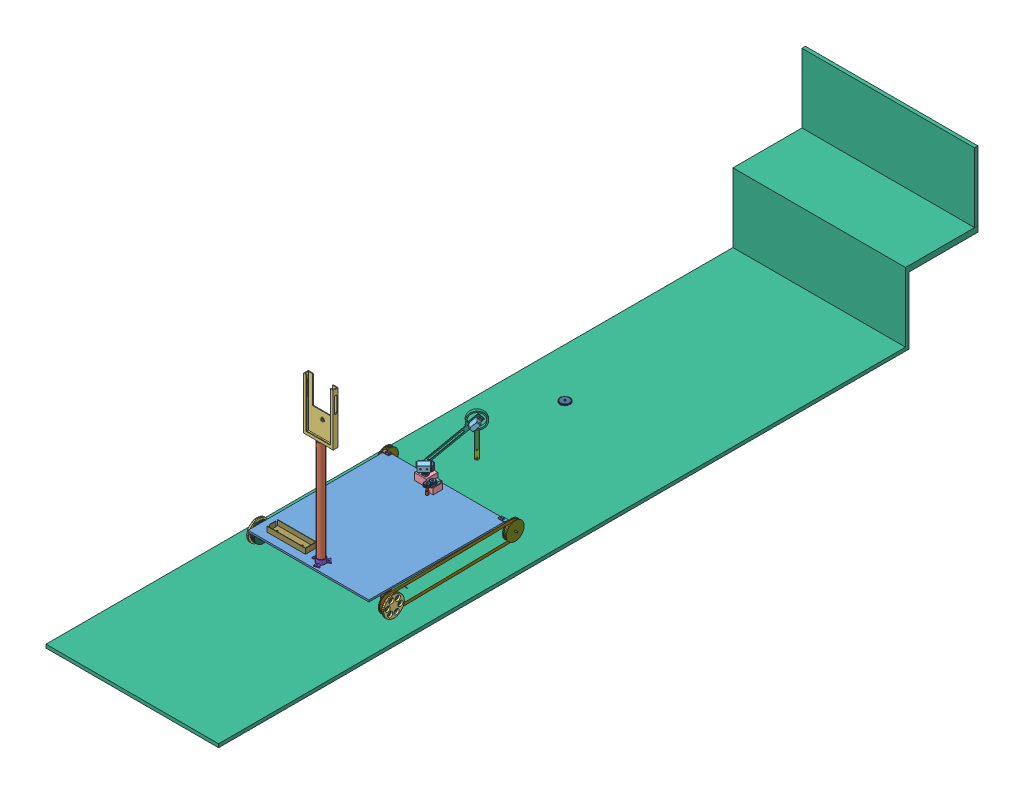
SolidWorks assembly New_pro_1, configuration Default. Lengths in mm.
Overall size (500 532.63 2200).
40 component instances, 28 part files, 93 mates.
Components (placement in the parent):
- pla_form^New_pro_1-1: pla_form^New_pro_1 [Default] at (-4.0742 7.4125 270.787) size (350 5 400) (virtual)
- _1^New_pro_1-1: _1^New_pro_1 [Default] at (145.9258 -17.5875 455.5975) x (0 0 1) z (0 -1 0) size (30 22 37) (virtual)
- _1^New_pro_1-8: _1^New_pro_1 [Default] at (-204.0742 -17.5875 461.231) x (0 0 -1) z (0 -1 0) size (30 22 37) (virtual)
- wheel^New_pro_1-1: wheel^New_pro_1 [Default] at (-218.1155 -17.5875 461.231) x (0 0.865796 0.500397) z (0 0.500397 -0.865796) size (59.99 15 60) (virtual)
- wheel^New_pro_1-2: wheel^New_pro_1 [Default] at (163.0568 -17.5875 455.5975) x (0 0.179754 0.983712) z (0 -0.983712 0.179754) size (59.99 15 60) (virtual)
- Part4^New_pro_1-1: Part4^New_pro_1 [Default] at (-33.2415 12.4125 135.9709) x (0 0 -1) z (1 0 0) size (27 17 17) (virtual)
- servo motor assembly-1: servo motor assembly [Default] at (-33.7415 18.9125 135.9709) x (0 0 -1) z (1 0 0) size (32 28.96 12.1)
- Part5^New_pro_1-1: Part5^New_pro_1 [Default] at (-28.5061 -55 17.1812) x (1 0 0) z (0 -1 0) size (500 2200 410) (virtual)
- Part6^New_pro_1-1: Part6^New_pro_1 [Default] at (-32.2713 -39 155.8027) x (-0.903083 0 0.429467) z (0.314627 0.680661 0.661597) size (5 32 32) (virtual)
- Part7^New_pro_1-1: Part7^New_pro_1 [Default] at (-28.8372 2.4125 426.5787) x (-1 0 0) z (0 0 -1) size (24 10 24) (hidden, virtual)
- Part2^New_pro_1-1: Part2^New_pro_1 [Default] at (-19.1677 15.4125 480.0726) size (41 13 43.04) (virtual)
- Part3^New_pro_1-1: Part3^New_pro_1 [Default] at (-33.4223 -7.6112 159.2036) x (-0.903083 0 0.429467) z (-0.429467 0 -0.903083) size (16 79 9.12) (virtual)
- spur gear_am-2: spur gear_am [Metric - Spur gear 1M 15T 20PA 7FW ---S15N75H50L5N] at (-34.496 40.484 156.9459) x (0 -1 0) z (-0.158866 0 0.9873) size (7 16.86 16.95)
- Part8^New_pro_1-1: Part8^New_pro_1 [Default] at (-34.496 22.4125 156.9459) x (0 -1 0) z (0.953182 0 0.302396) size (10 7.1 7.1) (virtual)
- spur gear_am-3: spur gear_am [Metric - Spur gear 1M 15T 20PA 7FW ---S15N75H50L5N] at (-33.7415 39.8334 141.4709) x (0 -1 0) z (-0.735928 0 0.67706) size (7 16.86 16.95)
- Part1^New_pro_1-1: Part1^New_pro_1 [Default] at (-116.5843 12.4125 467.4581) x (1 0 0) z (0 1 0) size (112 32 15) (virtual)
- Copy of _1^New_pro_1-1: Copy of _1^New_pro_1 [Default] at (-207.0742 -56.5875 111.1318) x (0 0 -1) z (1 0 0) size (24.36 29.9 20) (virtual)
- Part9^New_pro_1-1: Part9^New_pro_1 [Default] at (-234.0598 -12.5875 96.0801) x (0 -0.898887 0.43818) z (0 0.43818 0.898887) size (3 400 3) (virtual)
- Part10^New_pro_1-1: Part10^New_pro_1 [Default] at (-231.0598 -11.8664 -1281.8903) x (0 -0.009936 0.999951) z (0 -0.999951 -0.009936) size (189.54 3 184.99) (hidden, virtual)
- Part10^New_pro_1-2: Part10^New_pro_1 [Default] at (576.093 -12.5875 96.0801) x (0 0.412111 -0.911134) z (0 0.911134 0.412111) size (189.54 3 184.99) (hidden, virtual)
- Part11^New_pro_1-1: Part11^New_pro_1 [Default] at (154.1522 -17.5875 455.5975) x (0 0.999935 -0.011442) z (1 0 0) size (52 52 11) (virtual)
- Copy (2) of Part11^New_pro_1-1: Copy (2) of Part11^New_pro_1 [Default] at (154.1522 -12.5875 96.0801) x (0 -0.918195 0.39613) z (1 0 0) size (52 52 11) (virtual)
- Part12^New_pro_1-1: Part12^New_pro_1 [Default] at (-15.4589 -12.5875 96.0801) x (1 0 0) z (0 -0.39234 -0.91982) size (15 6 6) (virtual)
- Part13^New_pro_1-1: Part13^New_pro_1 [Default] at (150.1522 -17.5801 455.1293) x (0 0.015746 -0.999876) z (0 -0.999876 -0.015746) size (406.68 8 48.4) (virtual)
- Copy of Copy of _1^New_pro_1-1: Copy of Copy of _1^New_pro_1 [Default] at (148.9258 -56.5875 104.8855) x (0 0 1) z (-1 0 0) size (23.36 29.9 20) (virtual)
- Copy (2) of Part11^New_pro_1-2: Copy (2) of Part11^New_pro_1 [Default] at (-210.2461 -12.5875 96.0801) x (0 0.790861 0.611996) z (1 0 0) size (52 52 11) (virtual)
- Part11^New_pro_1-2: Part11^New_pro_1 [Default] at (-210.2461 -17.5875 461.231) x (0 -0.929495 -0.368836) z (1 0 0) size (52 52 11) (virtual)
- Part14^New_pro_1-1: Part14^New_pro_1 [Default] at (-19.1677 317.6266 480.0726) x (0.999891 0 -0.014732) z (0 -1 0) size (20 20 300) (virtual)
- Part15^New_pro_1-1: Part15^New_pro_1 [Default] at (-210.5461 6.6125 -555.6534) x (0 0 -1) z (-1 0 0) size (200 1 5) (hidden, virtual)
- Part16^New_pro_1-1: Part16^New_pro_1 [Default] at (-19.6149 317.6266 480.0736) x (0.999998 0 -0.002153) z (0.002153 0 0.999998) size (86 155 14) (virtual)
- spur gear_am-4: spur gear_am [Metric - Spur gear 1M 27T 20PA 4FW ---S27N75H50L5N] at (-40.7254 42.8766 -248.5569) x (0 -1 0) z (-0.499439 0 0.866349) size (4 28.93 28.98)
- servo motor assembly-2: servo motor assembly [Default] at (-71.3814 15.9125 130.1318) x (-1 0 0) z (0 0 -1) size (32 28.96 12.1)
- Part17^New_pro_1-1: Part17^New_pro_1 [Default] at (-71.3814 32.4125 123.1318) x (0 -1 0) z (0 0 1) size (20 60 34) (virtual)
- spur gear_am-5: spur gear_am [Metric - Spur gear 1M 15T 20PA 7FW ---S15N75H50L5N] at (-65.8814 36.9125 130.1318) x (0 1 0) z (-0.616937 0 -0.787012) size (7 16.86 16.95)
- spur gear_am-7: spur gear_am [Metric - Spur gear 1M 30T 14.5PA 12FW ---S30N75H50L0.8N] at (-79.7625 32.4125 112.424) x (0 1 0) z (-0.414876 0 0.909878) size (12 31.9 32)
- Copy of Part4^New_pro_1-1: Copy of Part4^New_pro_1 [Default] at (-62.3984 52.9125 139.1016) x (0.707107 0 -0.707107) z (0 1 0) size (27 37 17) (virtual)
- servo motor assembly-3: servo motor assembly [Default] at (-67.3481 52.4125 134.1518) x (-0.707107 0 0.707107) z (0 -1 0) size (32 28.96 12.1)
- Part18^New_pro_1-1: Part18^New_pro_1 [Default] at (-78.3083 52.4125 115.4135) x (0.5 0.707107 -0.5) z (-0.707107 0 -0.707107) size (175.02 47.86 8.5) (virtual)
- servo motor assembly-4: servo motor assembly [Default] at (0.9491 150.9387 53.8338) x (-0.5 -0.707107 0.5) z (0.5 -0.707107 -0.5) size (32 28.96 12.1)
- Copy of Copy of Part18^New_pro_1-1: Copy of Copy of Part18^New_pro_1 [Default] at (-11.1501 54.8278 36.2345) x (0 -1 0) z (-0.707107 0 -0.707107) size (110.5 10.5 3) (virtual)
Mates (geometry in assembly coordinates):
- Coincident1: coincident anti-aligned: plane of pla_form^New_pro_1-1 through (-4.0742 7.4125 270.787) normal (0 -1 0); plane of _1^New_pro_1-1 through (143.9258 7.4125 440.5975) normal (0 1 0)
- Coincident2: coincident aligned: plane of pla_form^New_pro_1-1 through (145.9258 12.4125 106.1318) normal (1 0 0); plane of _1^New_pro_1-1 through (145.9258 -17.5875 455.5975) normal (1 0 0)
- Coincident12: coincident aligned: plane of _1^New_pro_1-8 through (-204.0742 -17.5875 461.231) normal (-1 0 0); plane of pla_form^New_pro_1-1 through (-204.0742 12.4125 106.1318) normal (-1 0 0)
- Coincident14: coincident anti-aligned: plane of pla_form^New_pro_1-1 through (-4.0742 7.4125 270.787) normal (0 -1 0); plane of _1^New_pro_1-8 through (-202.0742 7.4125 476.231) normal (0 1 0)
- Concentric1: concentric aligned: cylinder of _1^New_pro_1-8 through (-202.0742 -17.5875 461.231) axis (-1 0 0) radius 7.5; cylinder of wheel^New_pro_1-1 through (-208.1155 -17.5875 461.231) axis (-1 0 0) radius 5.1
- Concentric2: concentric aligned: cylinder of _1^New_pro_1-1 through (143.9258 -17.5875 455.5975) axis (1 0 0) radius 7.5; cylinder of wheel^New_pro_1-2 through (153.0568 -17.5875 455.5975) axis (1 0 0) radius 5.1
- Coincident18: coincident anti-aligned: plane of pla_form^New_pro_1-1 through (-4.0742 12.4125 270.787) normal (0 1 0); plane of Part4^New_pro_1-1 through (-33.2415 12.4125 135.9709) normal (0 -1 0)
- Parallel1: parallel anti-aligned: plane of pla_form^New_pro_1-1 through (145.9258 12.4125 106.1318) normal (1 0 0); plane of Part4^New_pro_1-1 through (-41.7415 13.9125 135.9709) normal (-1 0 0)
- Coincident22: coincident anti-aligned: plane of Part4^New_pro_1-1 through (-39.7415 29.4125 147.4709) normal (1 0 0); plane of servo motor assembly-1 through (-39.7415 28.9125 135.9709) normal (-1 0 0)
- Coincident23: coincident anti-aligned: plane of Part4^New_pro_1-1 through (-33.2415 13.9125 135.9709) normal (0 1 0); plane of servo motor assembly-1 through (-33.7415 13.9125 135.9709) normal (0 -1 0)
- Parallel3: parallel anti-aligned: plane of pla_form^New_pro_1-1 through (-4.0742 7.4125 270.787) normal (0 -1 0); plane of Part5^New_pro_1-1 through (-28.5061 -55 17.1812) normal (0 1 0)
- Coincident29: coincident anti-aligned: plane of Part4^New_pro_1-1 through (-39.7415 29.4125 147.4709) normal (0 0 -1); plane of servo motor assembly-1 through (-27.7415 28.9125 147.4709) normal (0 0 1)
- Parallel4: parallel anti-aligned: plane of Part5^New_pro_1-1 through (-28.5061 -55 17.1812) normal (0 1 0); plane of Part7^New_pro_1-1 through (-28.8372 2.4125 426.5787) normal (0 -1 0)
- Parallel5: parallel: plane of pla_form^New_pro_1-1 through (-204.0742 12.4125 106.1318) normal (0 0 -1); line of Part3^New_pro_1-1 through (-36.1315 -12.6112 160.492) axis (0 -1 0)
- Concentric3: concentric aligned: circle of Part6^New_pro_1-1; circle of Part3^New_pro_1-1
- Concentric4: concentric anti-aligned: cylinder of pla_form^New_pro_1-1 through (-34.496 2.4125 156.9459) axis (0 1 0) radius 2.5; cylinder of Part3^New_pro_1-1 through (-34.496 36.3888 156.9459) axis (0 -1 0) radius 2.5
- Distance1: distance = 0.5 mm anti-aligned: plane of Part6^New_pro_1-1 through (-36.7867 -39 157.9501) normal (-0.903083 0 0.429467); plane of Part3^New_pro_1-1 through (-38.2789 -12.6112 155.9766) normal (0.903083 0 -0.429467)
- Concentric5: concentric anti-aligned: cylinder of Part3^New_pro_1-1 through (-34.496 36.3888 156.9459) axis (0 -1 0) radius 2.5; cylinder of spur gear_am-2 through (-34.496 -9.516 156.9459) axis (0 1 0) radius 2.5
- Tangent2: tangent anti-aligned: plane of Part5^New_pro_1-1 through (-28.5061 -55 17.1812) normal (0 1 0); cylinder of Part6^New_pro_1-1 through (-36.7867 -39 157.9501) axis (0.903083 0 -0.429467) radius 16
- Concentric7: concentric anti-aligned: cylinder of Part3^New_pro_1-1 through (-34.496 36.3888 156.9459) axis (0 -1 0) radius 2.5; cylinder of Part8^New_pro_1-1 through (-34.496 12.4125 156.9459) axis (0 1 0) radius 2.55
- Coincident37: coincident anti-aligned: plane of pla_form^New_pro_1-1 through (-4.0742 12.4125 270.787) normal (0 1 0); plane of Part8^New_pro_1-1 through (-34.496 12.4125 156.9459) normal (0 -1 0)
- Concentric9: concentric anti-aligned: circle of servo motor assembly-1; cylinder of spur gear_am-3 through (-33.7415 -10.1666 141.4709) axis (0 1 0) radius 2.5
- Coincident38: coincident anti-aligned: plane of pla_form^New_pro_1-1 through (-4.0742 12.4125 270.787) normal (0 1 0); plane of Part1^New_pro_1-1 through (-116.5843 12.4125 467.4581) normal (0 -1 0)
- Lock1: lock: unknown of _1^New_pro_1-8; unknown of pla_form^New_pro_1-1
- Lock2: lock: unknown of _1^New_pro_1-8; unknown of _1^New_pro_1-1
- Lock8: lock: unknown of Part7^New_pro_1-1; unknown of pla_form^New_pro_1-1
- Lock9: lock: unknown of Part3^New_pro_1-1; unknown of spur gear_am-2
- Lock10: lock: unknown of pla_form^New_pro_1-1; unknown of Part4^New_pro_1-1
- Lock11: lock: unknown of pla_form^New_pro_1-1; unknown of Part1^New_pro_1-1
- Distance2: distance = 16.0413 mm aligned: plane of wheel^New_pro_1-1 through (-218.1155 -17.5875 461.231) normal (1 0 0); plane of _1^New_pro_1-8 through (-202.0742 -17.5875 461.231) normal (1 0 0)
- Distance3: distance = 19.131 mm aligned: plane of wheel^New_pro_1-2 through (163.0568 -17.5875 455.5975) normal (-1 0 0); plane of _1^New_pro_1-1 through (143.9258 -17.5875 455.5975) normal (-1 0 0)
- Distance5: distance = 55.3906 mm aligned: plane of wheel^New_pro_1-1 through (-223.1155 -17.5875 461.231) normal (-1 0 0); plane of Part5^New_pro_1-1 through (-278.5061 -65 1017.1812) normal (-1 0 0)
- Coincident60: coincident aligned: cylinder of Part9^New_pro_1-1 through (165.9402 -12.5875 96.0801) axis (-1 0 0) radius 1.5; circle of Part10^New_pro_1-2
- Coincident65: coincident aligned: plane of Part9^New_pro_1-1 through (-234.0598 -12.5875 96.0801) normal (-1 0 0); plane of Part10^New_pro_1-1 through (-234.0598 -11.8664 -1281.8903) normal (-1 0 0)
- Concentric16: concentric aligned: cylinder of wheel^New_pro_1-2 through (153.0568 -17.5875 455.5975) axis (1 0 0) radius 3.1; cylinder of Part11^New_pro_1-1 through (159.6522 -17.5875 455.5975) axis (1 0 0) radius 24
- Distance6: distance = 28.0715 mm aligned: plane of spur gear_am-2 through (-34.496 40.484 156.9459) normal (0 1 0); plane of pla_form^New_pro_1-1 through (-4.0742 12.4125 270.787) normal (0 1 0)
- Concentric19: concentric anti-aligned: cylinder of Part9^New_pro_1-1 through (165.9402 -12.5875 96.0801) axis (-1 0 0) radius 1.5; cylinder of Copy (2) of Part11^New_pro_1-1 through (125.6522 -12.5875 96.0801) axis (1 0 0) radius 2
- Coincident75: coincident aligned: plane of Part11^New_pro_1-1 through (159.6522 -17.5875 455.5975) normal (1 0 0); plane of Copy (2) of Part11^New_pro_1-1 through (159.6522 -12.5875 96.0801) normal (1 0 0)
- Concentric20: concentric aligned: cylinder of Part9^New_pro_1-1 through (165.9402 -12.5875 96.0801) axis (-1 0 0) radius 1.5; cylinder of Part12^New_pro_1-1 through (-0.4589 -12.5875 96.0801) axis (-1 0 0) radius 3
- Concentric23: concentric anti-aligned: cylinder of Part11^New_pro_1-1 through (125.6522 -17.5875 455.5975) axis (1 0 0) radius 3.15; cylinder of Part13^New_pro_1-1 through (158.1522 -17.5875 455.5975) axis (-1 0 0) radius 24
- Distance7: distance = 3.4046 mm anti-aligned: plane of wheel^New_pro_1-2 through (163.0568 -17.5875 455.5975) normal (-1 0 0); plane of Part11^New_pro_1-1 through (159.6522 -17.5875 455.5975) normal (1 0 0)
- Coincident77: coincident aligned: circle of Part11^New_pro_1-1; circle of Part13^New_pro_1-1
- Coincident78: coincident anti-aligned: plane of pla_form^New_pro_1-1 through (-4.0742 12.4125 270.787) normal (0 1 0); plane of Copy of _1^New_pro_1-1 through (-187.0742 12.4125 106.1318) normal (0 -1 0)
- Coincident79: coincident anti-aligned: plane of pla_form^New_pro_1-1 through (-204.0742 12.4125 106.1318) normal (-1 0 0); plane of Copy of _1^New_pro_1-1 through (-204.0742 -56.5875 111.1318) normal (1 0 0)
- Coincident80: coincident aligned: plane of pla_form^New_pro_1-1 through (-204.0742 12.4125 106.1318) normal (0 0 -1); plane of Copy of _1^New_pro_1-1 through (-187.0742 12.4125 106.1318) normal (0 0 -1)
- Concentric24: concentric aligned: circle of Copy of _1^New_pro_1-1; cylinder of Part9^New_pro_1-1 through (165.9402 -12.5875 96.0801) axis (-1 0 0) radius 1.5
- Lock12: lock: unknown of pla_form^New_pro_1-1; unknown of Copy of _1^New_pro_1-1
- Coincident83: coincident anti-aligned: plane of pla_form^New_pro_1-1 through (145.9258 12.4125 106.1318) normal (1 0 0); plane of Copy of Copy of _1^New_pro_1-1 through (145.9258 -56.5875 104.8855) normal (-1 0 0)
- Coincident84: coincident anti-aligned: plane of pla_form^New_pro_1-1 through (-4.0742 12.4125 270.787) normal (0 1 0); plane of Copy of Copy of _1^New_pro_1-1 through (128.9258 12.4125 114.8855) normal (0 -1 0)
- Coincident85: coincident aligned: plane of pla_form^New_pro_1-1 through (-204.0742 12.4125 -325.1759) normal (0 0 -1); plane of Copy of Copy of _1^New_pro_1-1 through (128.9258 12.4125 -325.1759) normal (0 0 -1)
- Lock13: lock: unknown of pla_form^New_pro_1-1; unknown of Copy of Copy of _1^New_pro_1-1
- Concentric25: concentric anti-aligned: cylinder of Part9^New_pro_1-1 through (165.9402 -12.5875 96.0801) axis (-1 0 0) radius 1.5; cylinder of Copy (2) of Part11^New_pro_1-2 through (-238.7461 -12.5875 96.0801) axis (1 0 0) radius 2
- Coincident89: coincident aligned: plane of Copy (2) of Part11^New_pro_1-2 through (-215.7461 -12.5875 96.0801) normal (-1 0 0); plane of Part11^New_pro_1-2 through (-215.7461 -17.5875 461.231) normal (-1 0 0)
- Concentric26: concentric anti-aligned: cylinder of wheel^New_pro_1-1 through (-208.1155 -17.5875 461.231) axis (-1 0 0) radius 5.1; cylinder of Part11^New_pro_1-2 through (-238.7461 -17.5875 461.231) axis (1 0 0) radius 3.15
- Coincident90: coincident anti-aligned: plane of pla_form^New_pro_1-1 through (-4.0742 12.4125 270.787) normal (0 1 0); plane of Part2^New_pro_1-1 through (-19.1677 12.4125 480.0726) normal (0 -1 0)
- Lock14: lock: unknown of pla_form^New_pro_1-1; unknown of Part2^New_pro_1-1
- Concentric27: concentric anti-aligned: cylinder of Part2^New_pro_1-1 through (-19.1677 25.4125 480.0726) axis (0 -1 0) radius 10; cylinder of Part14^New_pro_1-1 through (-19.1677 17.6266 480.0726) axis (0 1 0) radius 10
- Tangent3: tangent aligned: cylinder of Part11^New_pro_1-2 through (-204.7461 -17.5875 -515.0671) axis (1 0 0) radius 24; plane of Part15^New_pro_1-1
- Distance8: distance = 2.6719 mm aligned: plane of Part11^New_pro_1-2 through (-204.7461 -17.5875 461.231) normal (1 0 0); plane of _1^New_pro_1-8 through (-202.0742 -17.5875 461.231) normal (1 0 0)
- Parallel6: parallel aligned: plane of pla_form^New_pro_1-1 through (-4.0742 12.4125 270.787) normal (0 1 0); plane of Part15^New_pro_1-1 through (-210.5461 6.6125 -555.6534) normal (0 1 0)
- Distance9: distance = 1.2 mm anti-aligned: plane of Part15^New_pro_1-1 through (-213.0461 6.4125 -455.6534) normal (-1 0 0); plane of Part11^New_pro_1-2 through (-214.2461 -17.5875 461.231) normal (1 0 0)
- Tangent4: tangent anti-aligned: cylinder of Part11^New_pro_1-2 through (-204.7461 -17.5875 461.231) axis (1 0 0) radius 24; plane of Part15^New_pro_1-1 through (-210.5461 6.4125 -555.6534) normal (0 -1 0)
- Concentric28: concentric aligned: cylinder of Part14^New_pro_1-1 through (-19.1677 17.6266 480.0726) axis (0 1 0) radius 10; cylinder of Part16^New_pro_1-1 through (-19.1677 312.6266 480.0726) axis (0 1 0) radius 4.5
- Coincident91: coincident anti-aligned: plane of Part14^New_pro_1-1 through (-19.1677 317.6266 480.0726) normal (0 1 0); plane of Part16^New_pro_1-1 through (-19.6149 317.6266 480.0736) normal (0 -1 0)
- Lock15: lock: unknown of pla_form^New_pro_1-1; unknown of Part14^New_pro_1-1
- Concentric29: concentric anti-aligned: cylinder of Part9^New_pro_1-1 through (165.9402 -12.5875 96.0801) axis (-1 0 0) radius 1.5; cylinder of Copy of Copy of _1^New_pro_1-1 through (145.9258 -12.5875 96.0801) axis (1 0 0) radius 2
- Coincident100: coincident anti-aligned: plane of pla_form^New_pro_1-1 through (-4.0742 12.4125 270.787) normal (0 1 0); plane of Part17^New_pro_1-1 through (-71.3814 12.4125 123.1318) normal (0 -1 0)
- Coincident101: coincident aligned: plane of pla_form^New_pro_1-1 through (-204.0742 12.4125 106.1318) normal (0 0 -1); plane of Part17^New_pro_1-1 through (-54.3814 12.4125 106.1318) normal (0 0 -1)
- Coincident102: coincident anti-aligned: plane of servo motor assembly-2 through (-71.3814 25.9125 124.1318) normal (0 0 -1); plane of Part17^New_pro_1-1 through (-82.8814 30.4125 124.1318) normal (0 0 1)
- Coincident103: coincident anti-aligned: plane of servo motor assembly-2 through (-82.8814 15.9125 124.1318) normal (-1 0 0); plane of Part17^New_pro_1-1 through (-82.8814 30.4125 124.1318) normal (1 0 0)
- Coincident105: coincident aligned: plane of servo motor assembly-2 through (-71.3814 32.4125 130.1318) normal (0 1 0); plane of Part17^New_pro_1-1 through (-71.3814 32.4125 123.1318) normal (0 1 0)
- Concentric32: concentric anti-aligned: cylinder of servo motor assembly-2 through (-65.8814 -13.7876 130.1318) axis (0 1 0) radius 0.5; cylinder of spur gear_am-5 through (-65.8814 86.9125 130.1318) axis (0 -1 0) radius 2.5
- Coincident108: coincident anti-aligned: plane of servo motor assembly-2 through (-68.7668 36.9125 128.6362) normal (0 1 0); plane of spur gear_am-5 through (-65.8814 36.9125 130.1318) normal (0 -1 0)
- Parallel10: parallel aligned: plane of spur gear_am-5 through (-65.8814 43.9125 130.1318) normal (0 1 0); plane of spur gear_am-7 through (-79.7625 44.4125 112.424) normal (0 1 0)
- Lock17: lock: unknown of pla_form^New_pro_1-1; unknown of Part17^New_pro_1-1
- Tangent5: tangent: circle of spur gear_am-5; circle of spur gear_am-7
- Concentric35: concentric anti-aligned: cylinder of Part17^New_pro_1-1 through (-79.7625 27.4125 112.424) axis (0 1 0) radius 3.5; cylinder of spur gear_am-7 through (-79.7625 82.4125 112.424) axis (0 -1 0) radius 0.4
- Coincident115: coincident anti-aligned: plane of Part17^New_pro_1-1 through (-71.3814 32.4125 123.1318) normal (0 1 0); plane of spur gear_am-7 through (-79.7625 32.4125 112.424) normal (0 -1 0)
- Coincident118: coincident anti-aligned: plane of Copy of Part4^New_pro_1-1 through (-82.5509 46.4125 135.2125) normal (0.707107 0 -0.707107); plane of servo motor assembly-3 through (-82.5509 52.4125 135.2125) normal (-0.707107 0 0.707107)
- Coincident119: coincident anti-aligned: plane of Copy of Part4^New_pro_1-1 through (-82.5509 46.4125 135.2125) normal (0 1 0); plane of servo motor assembly-3 through (-74.4192 46.4125 127.0808) normal (0 -1 0)
- Coincident120: coincident anti-aligned: plane of Copy of Part4^New_pro_1-1 through (-74.4192 52.9125 127.0808) normal (-0.707107 0 -0.707107); plane of servo motor assembly-3 through (-74.4192 52.4125 127.0808) normal (0.707107 0 0.707107)
- Coincident123: coincident anti-aligned: plane of spur gear_am-7 through (-79.7625 44.4125 112.424) normal (0 1 0); plane of Copy of Part4^New_pro_1-1 through (-63.459 44.4125 138.0409) normal (0 -1 0)
- Lock18: lock: unknown of spur gear_am-7; unknown of Copy of Part4^New_pro_1-1
- Concentric38: concentric anti-aligned: cylinder of servo motor assembly-3 through (-42.4579 52.4125 151.2639) axis (-0.707107 0 -0.707107) radius 0.5; cylinder of Part18^New_pro_1-1 through (-80.4296 52.4125 113.2922) axis (0.707107 0 0.707107) radius 2.5
- Coincident126: coincident anti-aligned: plane of servo motor assembly-3 through (-80.3486 50.9169 117.4538) normal (-0.707107 0 -0.707107); plane of Part18^New_pro_1-1 through (-78.3083 52.4125 115.4135) normal (0.707107 0 0.707107)
- Coincident143: coincident anti-aligned: plane of Part18^New_pro_1-1 through (0.8603 154.8278 36.2449) normal (-0.5 0.707107 0.5); plane of servo motor assembly-4 through (2.6281 154.8278 38.0127) normal (0.5 -0.707107 -0.5)
- Coincident144: coincident anti-aligned: plane of Part18^New_pro_1-1 through (-5.8897 164.3737 42.9949) normal (-0.5 -0.707107 0.5); plane of servo motor assembly-4 through (-0.3719 159.0704 41.0127) normal (0.5 0.707107 -0.5)
- Coincident147: coincident anti-aligned: plane of Part18^New_pro_1-1 through (-78.3083 52.4125 115.4135) normal (0.707107 0 0.707107); plane of servo motor assembly-4 through (-7.8897 150.9387 44.9949) normal (-0.707107 0 -0.707107)
- Concentric41: concentric anti-aligned: cylinder of servo motor assembly-4 through (24.7002 154.8278 72.0849) axis (-0.707107 0 -0.707107) radius 0.5; cylinder of Copy of Copy of Part18^New_pro_1-1 through (-13.2714 154.8278 34.1132) axis (0.707107 0 0.707107) radius 2.25
- Coincident149: coincident anti-aligned: plane of servo motor assembly-4 through (-11.845 151.7299 36.9294) normal (-0.707107 0 -0.707107); plane of Copy of Copy of Part18^New_pro_1-1 through (-11.1501 154.8278 36.2345) normal (0.707107 0 0.707107)
- Angle2: planar angle = 0.785398 rad anti-aligned: line of Part18^New_pro_1-1 through (-17.261 133.9682 50.1236) axis (-0.5 -0.707107 0.5); line of Copy of Part4^New_pro_1-1 through (-91.7433 46.4125 116.1206) axis (0.707107 0 -0.707107)
- Angle5: planar angle = 2.356194 rad aligned: line of Part18^New_pro_1-1 through (-17.261 133.9682 50.1236) axis (-0.5 -0.707107 0.5); line of Copy of Copy of Part18^New_pro_1-1 through (-16.9837 54.8278 37.8255) axis (0 1 0)
- Angle7: planar angle = 0.785398 rad aligned: plane of Part18^New_pro_1-1 through (-80.4296 52.4125 113.2922) normal (-0.707107 0 -0.707107); plane of Part17^New_pro_1-1 through (-54.3814 12.4125 106.1318) normal (0 0 -1)
